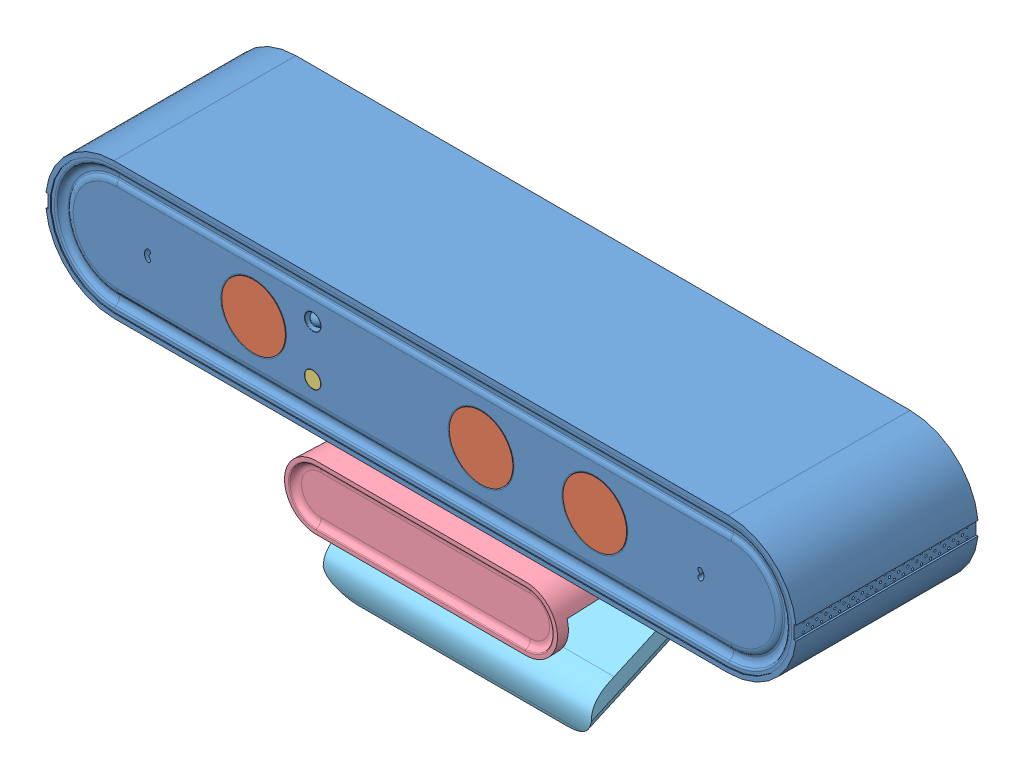
SolidWorks assembly Orbbec Astra Camera, configuration Default. Lengths in mm.
Overall size (164.85 67.21 60.73).
8 component instances, 5 part files, 6 mates.
Components (placement in the parent):
- Main_Body-1: Main_Body [Default] at origin size (164.85 35.05 58.1)
  - MainBody-1: MainBody [Default] at origin size (164.85 35.05 58.1)
  - Glass1-1: Glass1 [Default] at (72.1398 14.3643 -2.4) x (-0.923728 -0.383049 0) z (0 0 -1) size (14 14 1)
  - Glass1-2: Glass1 [Default] at (47.1398 14.3643 -2.4) x (-0.923728 -0.383049 0) z (0 0 -1) size (14 14 1)
  - Glass1-3: Glass1 [Default] at (-75 0 0) size (14 14 1)
  - SGlass1-1: SGlass1 [Default] at (-49.2381 -9.8042 -2.4) x (-0.923728 -0.383049 0) z (0 0 -1) size (3.5 3.5 1)
- Mount_Part1-1: Mount_Part1 [Default] at origin size (60.35 17.75 60.06)
- Mount_Part2-1: Mount_Part2 [Default] at (0 -22.2659 7.5198) x (1 0 0) z (0 -0.358691 0.933456) size (59.01 8.61 55.01)
Mates (geometry in assembly coordinates):
- Width2: width anti-aligned: plane of Mount_Part1-1 through (12.6 0 0) normal (-1 0 0); plane of Mount_Part1-1 through (-12.6 0 0) normal (1 0 0); plane of Main_Body-1/MainBody-1 through (12.5 -20 -7.5) normal (1 0 0); plane of Main_Body-1/MainBody-1 through (-12.5 -20 -7.5) normal (-1 0 0)
- Concentric5: concentric aligned: cylinder of Mount_Part1-1 through (-500000 -18.4 -11.25) axis (1 0 0) radius 0.75; cylinder of Main_Body-1/MainBody-1 through (-82.501 -18.4 -11.25) axis (1 0 0) radius 0.75
- Width3: width anti-aligned: plane of Mount_Part1-1 through (-21 -24.9 0) normal (1 0 0); plane of Mount_Part1-1 through (21 -24.9 0) normal (-1 0 0); plane of Mount_Part2-1 through (20 51.3047 -28.4871) normal (1 0 0); plane of Mount_Part2-1 through (-20 51.3047 -28.4871) normal (-1 0 0)
- Concentric6: concentric anti-aligned: cylinder of Mount_Part2-1 through (22 -31.4 -56.25) axis (-1 0 0) radius 0.75; cylinder of Mount_Part1-1 through (-22.5 -31.4 -56.25) axis (1 0 0) radius 0.75
- LimitAngle1: limit planar angle = 0 rad aligned: plane of Main_Body-1/MainBody-1 through (0 0 0) normal (0 1 0); plane of Mount_Part1-1 through (0 0 0) normal (0 1 0)
- LimitAngle2: limit planar angle = 0.366865 rad aligned: plane of Mount_Part2-1 through (0 -22.2659 7.5198) normal (0 0.933456 0.358691); plane of Mount_Part1-1 through (0 0 0) normal (0 1 0)
